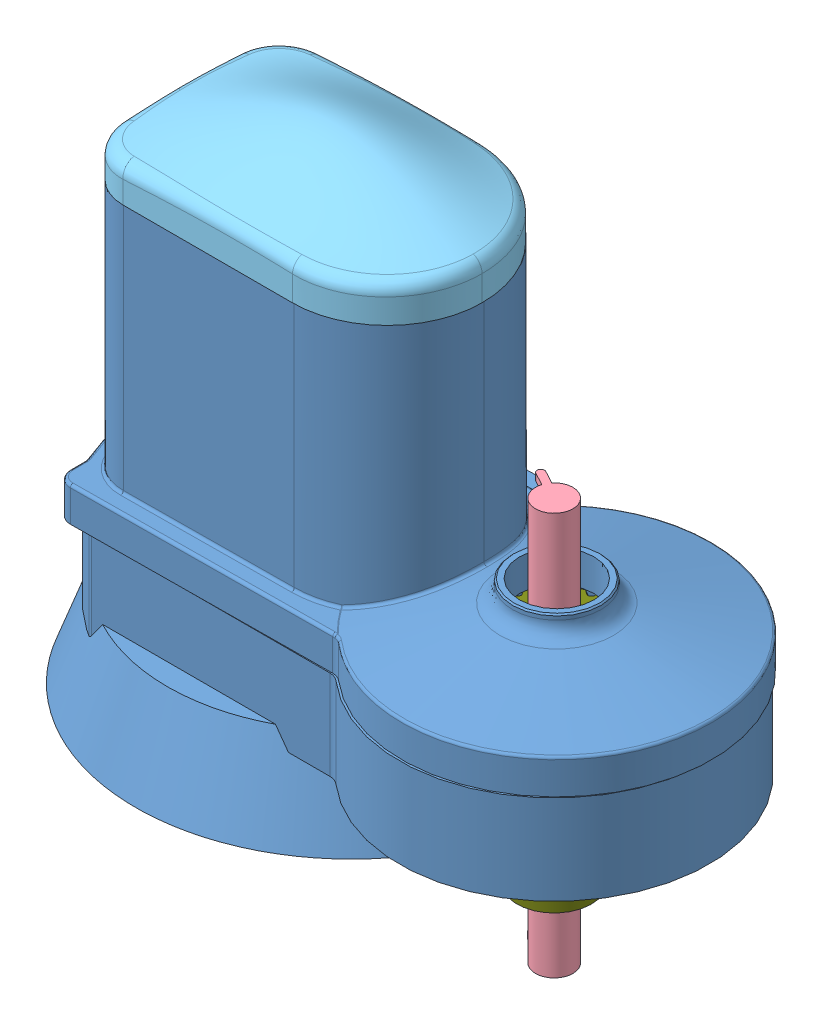
SolidWorks assembly neutral, configuration Default. Lengths in mm.
Overall size (454.45 443.9 318).
29 component instances, 23 part files, 35 mates.
Components (placement in the parent):
- block-1: block [Default] at (126.7686 58.2638 29.817) size (453.2 119.02 318)
- 2nd-shaft-1: 2nd-shaft [Default] at (-54.3586 204.793 35.6237) x (0.58464 0 -0.811293) z (0 -1 0) size (154.03 155.73 253.48) (flexible)
  - Part1 - Copy-1: Part1 - Copy [Default] at (39.9186 45.4622 -51.9509) size (88.21 88.13 251.48)
  - 4th-1: 4th [Default] at (39.9186 45.4622 -18.7909) x (-0.6004 -0.7997 0) z (0.7997 -0.6004 0) size (89.95 21.35 89.85)
  - 4th Mesh - Copy-1: 4th Mesh - Copy [Default] at (39.9186 45.4622 3.5591) x (0.967212 0.25397 0) z (-0.25397 0.967212 0) size (86.29 9.5 85.96)
  - 3rd Gear-1: 3rd Gear [Default] at (39.9186 45.4622 40.6691) x (-0.281078 0.959685 0) z (-0.959685 -0.281078 0) size (89.95 22.5 89.85)
  - gear3 mesh-1: gear3 mesh [Default] at (39.9186 45.4622 29.7091) x (0.241685 0.970355 0) z (-0.970355 0.241685 0) size (86.48 9.6 86.41)
  - 2nd gear-1: 2nd gear [Default] at (39.9186 45.4622 73.7691) x (0.182893 -0.983133 0) z (0.983133 0.182893 0) size (102.15 21.6 102.2)
  - Part3-1: Part3 [Default] at (39.9186 45.4622 38.17) x (0.888761 -0.458371 0) z (-0.458371 -0.888761 0) size (106.2 22 106.2)
  - base-1: base [Default] at (39.9186 45.4622 137.0291) x (0.811293 -0.58464 0) z (-0.58464 -0.811293 0) size (110 64.6 106)
  - reverse mesh-1: reverse mesh [Default] at (39.9186 45.4622 80.1091) x (0.5 0.866025 0) z (-0.866025 0.5 0) size (80 8.5 80)
  - 1st gear-1: 1st gear [Default] at (39.9186 45.4622 116.7091) x (0.948284 -0.317423 0) z (-0.317423 -0.948284 0) size (115.11 23.6 115.04)
  - reverse-1: reverse [Default] at (39.9186 45.4622 95.9165) x (-0.997854 -0.065483 0) z (0.065483 -0.997854 0) size (107.95 22 107.84)
  - reverse mesh-2: reverse mesh [Default] at (39.9186 45.4622 107.7091) x (0.608452 -0.793591 0) z (-0.793591 -0.608452 0) size (80 8.5 80)
- 1stshaft-1: 1stshaft [Default] at (-55.4373 -29.9162 -5.5745) x (-0.066805 0 0.997766) z (0 1 0) size (77.36 77.56 310)
- bearing1-1: bearing1 [Default] at (-55.4373 50.5838 -5.5745) x (-0.985087 0 -0.172057) z (-0.172057 0 0.985087) size (44.38 14.99 44.48)
- bearing2-1: bearing2 [Default] at (-55.4373 239.5138 -5.5745) x (0.844342 0 -0.535805) z (0.535805 0 0.844342) size (59.38 14.43 59.22)
- Assem1-1: Assem1 [Default] at (132.5358 -12.6199 35.0461) x (0.997011 0 0.077265) z (-0.077265 0 0.997011) size (195.12 146.24 195.18) (flexible)
  - diff-1: diff [Default] at (-6.1539 26.4978 -4.7679) size (195.12 146.24 195.18)
  - diffgearsmall-1: diffgearsmall [Default] at (-11.8929 12.9978 -4.7679) x (1 0 0) z (0 0.445148 -0.895457) size (22.67 53.82 54.31)
  - diffgearsmall-2: diffgearsmall [Default] at (-0.4149 12.9978 -4.7679) x (-1 0 0) z (0 -0.622917 0.782288) size (22.67 53.82 54.31)
- diffgearbig-1: diffgearbig [Default] at (126.7686 5.0369 29.817) x (0 -1 0) z (0.625851 0 0.779942) size (22.67 61.01 61.56)
- diffgearbig-2: diffgearbig [Default] at (126.7686 -0.6811 29.817) x (0 1 0) z (-0.777344 0 -0.629076) size (22.67 61.01 61.56)
- blockup-1: blockup [Default] at (127.0644 83.0638 28.2587) x (0.999963 0 -0.008545) z (0.008545 0 0.999963) size (399.91 205.51 224)
- rev-1: rev [Default] at (-70.1355 45.8638 52.9779) size (29.99 110 29.95)
- rev2-1: rev2 [Default] at (-70.1355 95.8638 52.9779) x (0.25593 0 -0.966695) z (0.966695 0 0.25593) size (59.97 20 59.87)
- axle-1: axle [Default] at (126.7686 -24.1754 29.817) x (-0.304422 0 0.952537) z (0 -1 0) size (27 40.03 100)
- axle-2: axle [Default] at (126.7686 66.9918 29.817) x (0.474153 0 -0.880442) z (0 1 0) size (27 40.03 100)
- blockup - Copy-1: blockup - Copy [Default] at (127.3931 83.0638 30.3383) size (222.45 55.95 144.6)
Mates (geometry in assembly coordinates):
- Concentric1: concentric anti-aligned: cylinder of block-1 through (5.8626 172.6075 29.817) axis (0 -1 0) radius 32.5; cylinder of 2nd-shaft-1/base-1 through (5.8626 54.2638 29.817) axis (0 1 0) radius 32.5
- Concentric2: concentric aligned: cylinder of block-1 through (23.3626 3.2638 74.817) axis (0 1 0) radius 4; cylinder of 2nd-shaft-1/base-1 through (23.3626 43.2638 74.817) axis (0 1 0) radius 4
- Coincident1: coincident anti-aligned: plane of block-1 through (-156.6457 58.2638 90.7205) normal (0 1 0); plane of 2nd-shaft-1/base-1 through (31.5668 58.2638 -27.7405) normal (0 -1 0)
- Concentric3: concentric aligned: cylinder of block-1 through (-55.4373 138.3946 -5.5745) axis (0 -1 0) radius 21.3305; cylinder of 1stshaft-1 through (-55.4373 36.0838 -5.5745) axis (0 -1 0) radius 10.5
- Coincident2: coincident aligned: plane of 2nd-shaft-1/4th-1 through (5.8626 223.5838 29.817) normal (0 1 0); plane of 1stshaft-1 through (-55.4373 223.5838 -5.5745) normal (0 1 0)
- Concentric4: concentric anti-aligned: cone of 1stshaft-1 through (-55.4373 239.5838 -5.5745) axis (0 1 0); cone of bearing1-1 through (-55.4373 53.8085 -5.5745) axis (0 -1 0)
- Coincident3: coincident aligned: plane of 1stshaft-1 through (-55.4373 65.5838 -5.5745) normal (0 1 0); plane of bearing1-1 through (-75.1378 65.5838 -9.0154) normal (0 1 0)
- Concentric5: concentric anti-aligned: cone of 1stshaft-1 through (-55.4373 239.5838 -5.5745) axis (0 1 0); cylinder of bearing2-1 through (-55.4373 222.0838 -5.5745) axis (0 -1 0) radius 22.5514
- Distance1: distance = 1.5 mm anti-aligned: plane of bearing2-1 through (-34.5047 225.0838 -18.8579) normal (0 -1 0); plane of 1stshaft-1 through (-55.4373 223.5838 -5.5745) normal (0 1 0)
- Concentric6: concentric aligned: cylinder of block-1 through (126.7686 33.4638 29.817) axis (0 1 0) radius 100; cylinder of Assem1-1/diff-1 through (126.7686 13.7779 29.817) axis (0 1 0) radius 16.5
- Concentric7: concentric anti-aligned: cylinder of Assem1-1/diff-1 through (126.7686 13.7779 29.817) axis (0 1 0) radius 16.5; cylinder of diffgearbig-1 through (126.7686 64.0369 29.817) axis (0 -1 0) radius 13.5
- Distance2: distance = 52 mm anti-aligned: plane of diffgearbig-1 through (115.3763 20.2979 41.9347) normal (0 -1 0); plane of Assem1-1/diff-1 through (126.7686 72.2979 29.817) normal (0 1 0)
- GearMate1: gear = 39.4 : 39.4 mm: circle of diffgearbig-1; circle of Assem1-1/diffgearsmall-1
- GearMate2: gear = 39.4 : 39.4 mm: circle of Assem1-1/diffgearsmall-2; circle of diffgearbig-1
- Concentric8: concentric anti-aligned: cylinder of Assem1-1/diff-1 through (126.7686 -14.4921 29.817) axis (0 -1 0) radius 14.2; cylinder of diffgearbig-2 through (126.7686 -59.6811 29.817) axis (0 1 0) radius 13.5
- Distance3: distance = 58 mm anti-aligned: plane of diffgearbig-2 through (126.1631 -15.9421 13.196) normal (0 1 0); plane of Assem1-1/diff-1 through (126.7686 -73.9421 29.817) normal (0 -1 0)
- GearMate3: gear = 39.4 : 39.4 mm: circle of Assem1-1/diffgearsmall-2; circle of diffgearbig-2
- Distance6: distance = 16.186 mm aligned: plane of Assem1-1/diff-1 through (126.7686 -73.9421 29.817) normal (0 -1 0); plane of block-1 through (126.7686 -57.7562 29.817) normal (0 -1 0)
- GearMate5: gear = 63.1 : 65 mm: circle of 1stshaft-1; circle of 2nd-shaft-1/4th-1
- GearMate6: gear = 73.33 : 53 mm: circle of 1stshaft-1; circle of 2nd-shaft-1/3rd Gear-1
- GearMate7: gear = 39 : 88 mm: circle of 2nd-shaft-1/2nd gear-1; circle of 1stshaft-1
- GearMate8: gear = 103 : 26 mm: circle of 1stshaft-1; circle of 2nd-shaft-1/1st gear-1
- GearMate9: gear = 183.6 : 45 mm: circle of 2nd-shaft-1/Part1 - Copy-1; circle of Assem1-1/diff-1
- Concentric9: concentric anti-aligned: cylinder of 1stshaft-1 through (-55.4373 265.5838 -5.5745) axis (0 -1 0) radius 17.5; cylinder of blockup-1 through (-55.4373 164.2784 -5.5745) axis (0 1 0) radius 17.5
- Coincident8: coincident anti-aligned: plane of block-1 through (-156.6457 58.2638 90.7205) normal (0 1 0); plane of blockup-1 through (-155.8191 58.2638 91.5819) normal (0 -1 0)
- Concentric12: concentric aligned: cylinder of block-1 through (-70.1355 100.6902 52.9779) axis (0 -1 0) radius 10; cylinder of rev-1 through (-70.1355 80.8638 52.9779) axis (0 -1 0) radius 10
- Coincident11: coincident anti-aligned: plane of block-1 through (51.2703 45.8638 -50.183) normal (0 1 0); plane of rev-1 through (-70.1355 45.8638 52.9779) normal (0 -1 0)
- Concentric13: concentric aligned: cylinder of rev-1 through (-70.1355 155.8638 52.9779) axis (0 -1 0) radius 10; cylinder of rev2-1 through (-70.1355 105.8638 52.9779) axis (0 -1 0) radius 15
- LimitDistance1: limit distance = 25 mm aligned: plane of rev2-1 through (-70.1355 115.8638 52.9779) normal (0 1 0); plane of rev-1 through (-70.1355 140.8638 52.9779) normal (0 1 0)
- Concentric14: concentric aligned: cylinder of diffgearbig-1 through (126.7686 64.0369 29.817) axis (0 -1 0) radius 13.5; cylinder of axle-2 through (126.7686 166.9918 29.817) axis (0 -1 0) radius 13.5
- Lock1: lock: unknown of ?; unknown of ?
- Concentric15: concentric aligned: cylinder of diffgearbig-2 through (126.7686 -59.6811 29.817) axis (0 1 0) radius 13.5; cylinder of axle-1 through (126.7686 -124.1754 29.817) axis (0 1 0) radius 13.5
- Lock2: lock: unknown of ?; unknown of ?
- Coincident12: coincident anti-aligned: plane of blockup-1 through (-1.1743 263.7758 29.3546) normal (0 1 0); plane of blockup - Copy-1 through (-614.2155 263.7758 30.3383) normal (0 -1 0)
- Coincident14: coincident aligned: circle of blockup-1; circle of blockup - Copy-1
